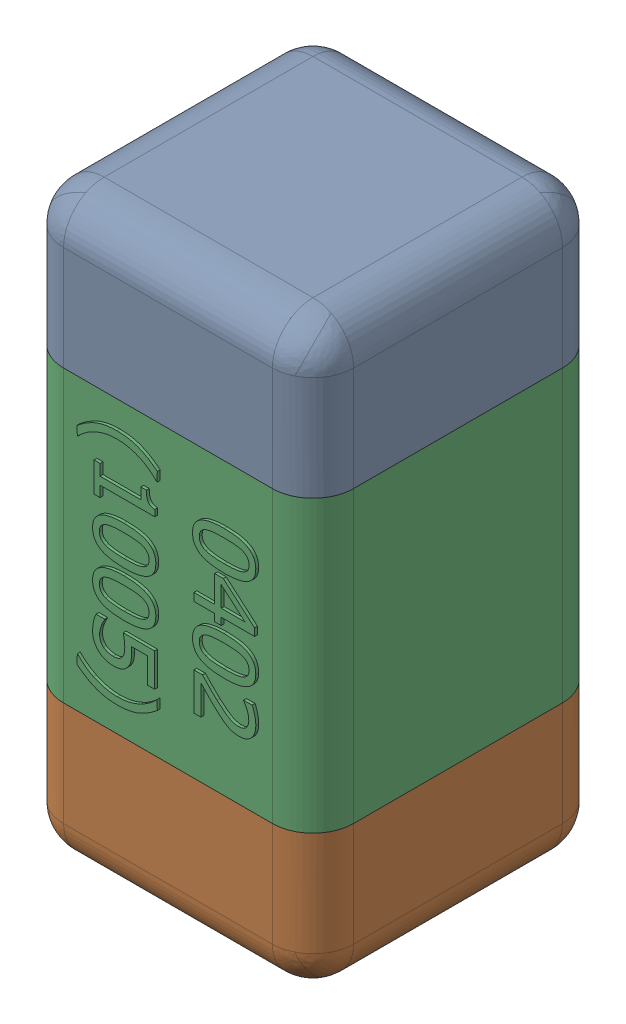
SolidWorks assembly C24, configuration Standard. Lengths in mm.
Overall size (0.51 1.01 0.51).
4 component instances, 3 part files, 0 mates.
Components (placement in the parent):
- C24-subassembly-1-1: C24-subassembly-1 [Standard] at (-9.1 -12.5001 0) x (0 -1 0) z (0 0 1) size (1.01 0.51 0.51)
  - User Library-0402_Cap-1: User Library-0402_Cap [Standard] at origin size (0.26 0.51 0.51)
  - User Library-0402_Cap-1-1: User Library-0402_Cap-1 [Standard] at origin size (0.26 0.5 0.51)
  - User Library-0402_Cap-2-1: User Library-0402_Cap-2 [Standard] at origin size (0.5 0.5 0.51)
